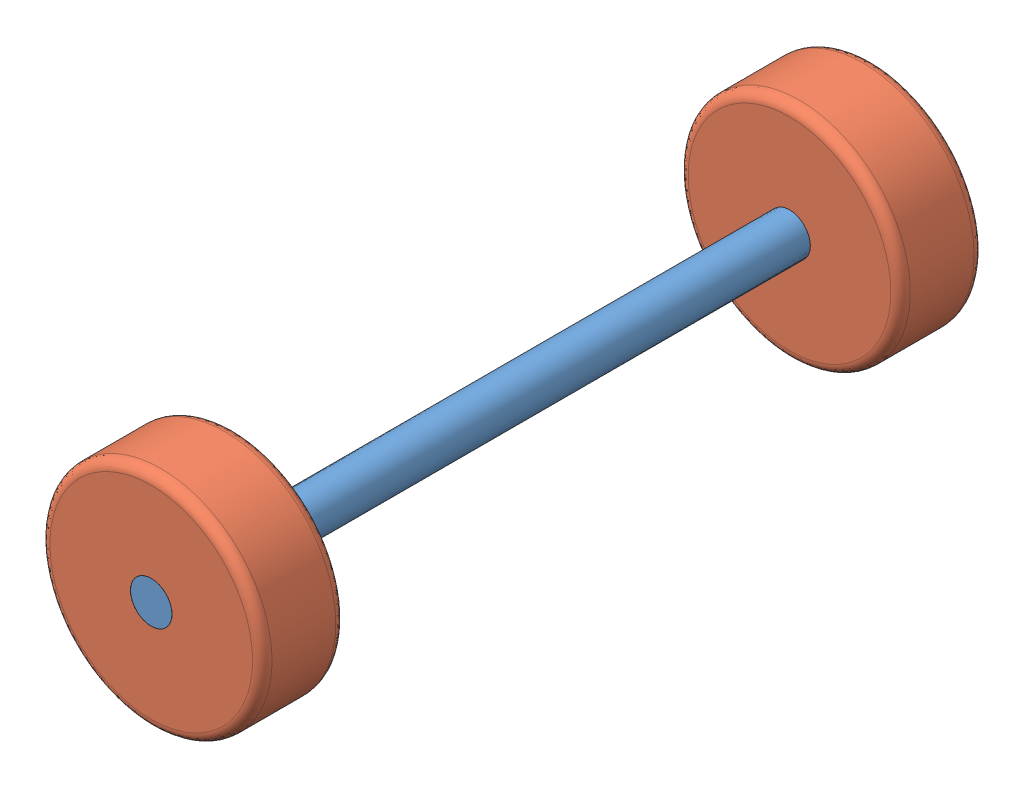
SolidWorks assembly rear_axle, configuration Default. Lengths in mm.
Overall size (253.73 253.73 660.4).
3 component instances, 2 part files, 7 mates.
Components (placement in the parent):
- rear_axle-1: rear_axle [Default] at origin size (38.1 38.1 660.4)
- rear_wheel-3: rear_wheel [Default] at (0 0 292.1) x (0.991546 0.129754 0) z (0 0 1) size (203.2 203.2 76.2)
- rear_wheel-4: rear_wheel [Default] at (0 0 -292.1) x (0.956311 0.29235 0) z (0 0 1) size (203.2 203.2 76.2)
Mates (geometry in assembly coordinates):
- Coincident1: coincident aligned: plane of rear_axle-1 through (0 0 0) normal (0 0 1)
- Coincident2: coincident aligned: plane of rear_axle-1 through (0 0 0) normal (0 1 0)
- Coincident3: coincident aligned: plane of rear_axle-1 through (0 0 0) normal (1 0 0)
- Concentric1: concentric aligned: cylinder of rear_axle-1 through (0 0 330.2) axis (0 0 -1) radius 19.05; cylinder of rear_wheel-3 through (0 0 330.2) axis (0 0 -1) radius 19.05
- Coincident4: coincident aligned: plane of rear_axle-1 through (0 0 330.2) normal (0 0 1); plane of rear_wheel-3 through (0 0 330.2) normal (0 0 1)
- Concentric2: concentric aligned: cylinder of rear_axle-1 through (0 0 330.2) axis (0 0 -1) radius 19.05; cylinder of rear_wheel-4 through (0 0 -254) axis (0 0 -1) radius 19.05
- Coincident5: coincident aligned: plane of rear_axle-1 through (0 0 -330.2) normal (0 0 -1); plane of rear_wheel-4 through (0 0 -330.2) normal (0 0 -1)
